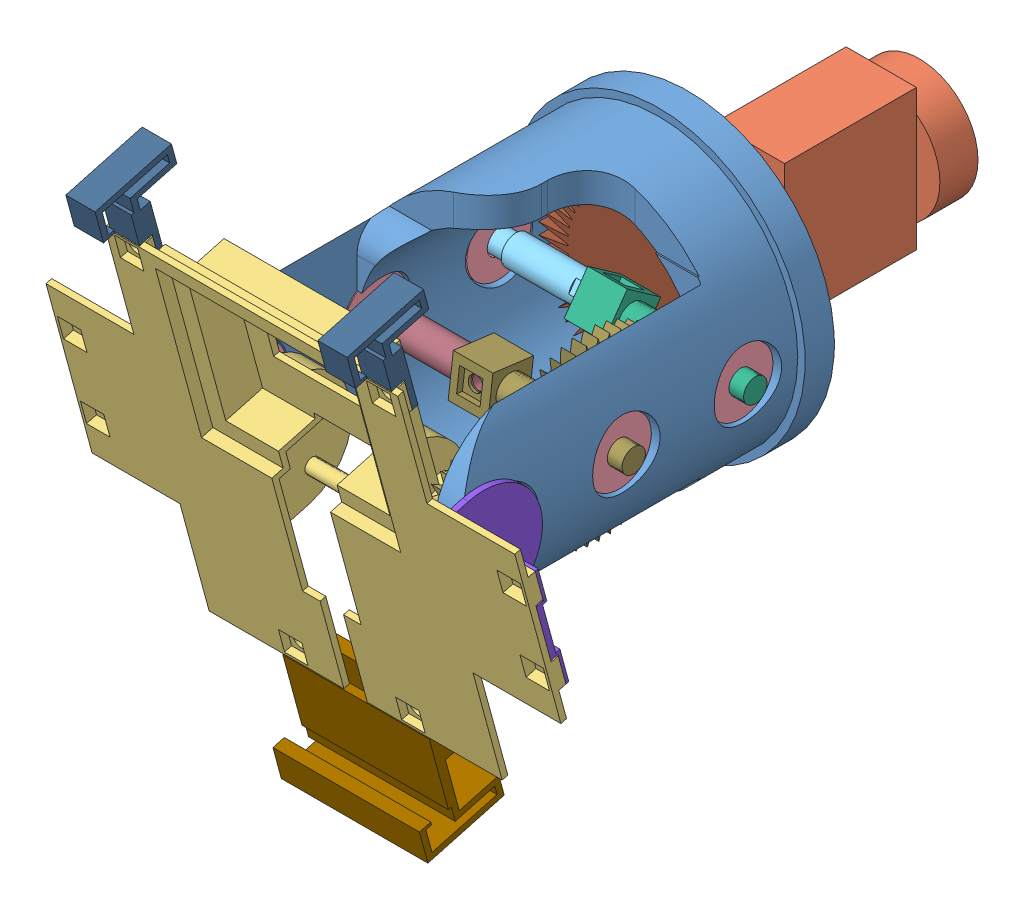
SolidWorks assembly Assemblagefinal, configuration Défaut. Lengths in mm.
Overall size (160 193.33 243.82).
20 component instances, 13 part files, 45 mates.
Components (placement in the parent):
- test taille plateforme3-1: test taille plateforme3 [Défaut] at (-13.313 4.6457 79) size (100 100 136)
- piece dessous-1: piece dessous [Défaut] at (-13.313 4.6457 58) size (40 48 68)
- Fixation Panneau2-1: Fixation Panneau2 [Défaut] at (-12.813 -1.2497 210.7139) x (-1 0 0) z (0 0.262019 -0.965063) size (160 136 37.5)
- Roulement-1: Roulement [Défaut] at (24.687 4.6457 106) x (0 0 -1) z (1 0 0) size (22 22 7)
- Roulement-2: Roulement [Défaut] at (24.687 4.6457 147.5) x (0 0 -1) z (1 0 0) size (22 22 7)
- Roulement-3: Roulement [Défaut] at (24.687 4.6457 189) x (0 0 -1) z (1 0 0) size (22 22 7)
- Roulement-4: Roulement [Défaut] at (-58.313 4.6457 189) x (0 0 -1) z (1 0 0) size (22 22 7)
- Roulement-5: Roulement [Défaut] at (-58.313 4.6457 147.5) x (0 0 -1) z (1 0 0) size (22 22 7)
- Roulement-6: Roulement [Défaut] at (-57.813 4.6457 106) x (0 0 -1) z (1 0 0) size (22 22 7)
- Roulement-7: Roulement [Défaut] at (-13.313 4.6457 1) x (0.817339 -0.576157 0) z (0 0 1) size (22 22 7)
- First engrenage2-1: First engrenage2 [Défaut] at (-45.313 5.0542 105.7118) x (0 -0.817119 0.576469) z (1 0 0) size (10 10 50)
- First engrenage1-1: First engrenage1 [Défaut] at (-45.313 4.6457 106) x (0 -0.817119 0.576469) z (1 0 0) size (30 30 55.5)
- Fixation de la fixation-1: Fixation de la fixation [Défaut] at (-60.813 18.5755 214.0242) x (1 0 0) z (0 0.262019 -0.965063) size (60 40 30)
- Fixation de la fixation2-1: Fixation de la fixation2 [Défaut] at (35.187 -20.027 203.5434) x (-1 0 0) z (0 0.262019 -0.965063) size (46 40 30)
- test accrochev1-1: test accrochev1 [Défaut] at (-37.813 -81.3084 186.9052) x (-1 0 0) z (0 -0.262019 0.965063) size (50 45.5 27)
- test accrochev2-1: test accrochev2 [Défaut] at (35.187 66.3461 226.9941) x (1 0 0) z (0 -0.262019 0.965063) size (10 31.5 27)
- test accrochev2-2: test accrochev2 [Défaut] at (-50.813 66.3461 226.9941) x (1 0 0) z (0 -0.262019 0.965063) size (10 31.5 27)
- Pièce3-1: Pièce3 [Défaut] at (-13.313 4.6457 95) x (-0.925124 0.379665 0) z (0 0 -1) size (70 70 36)
- Second engrenage2-1: Second engrenage2 [Défaut] at (-45.313 4.6457 147.5) x (0 -0.126763 -0.991933) z (1 0 0) size (60 60 55.5)
- Second engrenage1-1: Second engrenage1 [Défaut] at (-45.313 4.6457 147.5) x (0 -0.991933 0.126763) z (1 0 0) size (10 10 50)
Mates (geometry in assembly coordinates):
- Coaxiale6: concentric anti-aligned: cylinder of test taille plateforme3-1 through (-13.313 4.6457 184) axis (0 0 -1) radius 5.5; cylinder of piece dessous-1 through (-13.313 4.6457 58) axis (0 0 1) radius 5.5
- Parallèle4: parallel aligned: plane of test taille plateforme3-1 through (-51.313 4.6457 79) normal (1 0 0); plane of piece dessous-1 through (-4.2763 4.6457 58) normal (1 0 0)
- Coïncidente2: coincident anti-aligned: plane of test taille plateforme3-1 through (-13.313 4.6457 68) normal (0 0 -1); plane of piece dessous-1 through (-13.313 4.6457 68) normal (0 0 1)
- Coaxiale8: concentric anti-aligned: cylinder of test taille plateforme3-1 through (-63.313 4.6457 189) axis (1 0 0) radius 11.5; cylinder of Roulement-3 through (31.687 4.6457 189) axis (-1 0 0) radius 11
- Coïncidente3: coincident aligned: plane of test taille plateforme3-1 through (24.687 4.6457 239) normal (-1 0 0); plane of Roulement-3 through (24.687 4.6457 189) normal (-1 0 0)
- Coaxiale9: concentric anti-aligned: cylinder of test taille plateforme3-1 through (-63.313 4.6457 147.5) axis (1 0 0) radius 11.5; cylinder of Roulement-2 through (31.687 4.6457 147.5) axis (-1 0 0) radius 11
- Coïncidente4: coincident aligned: plane of test taille plateforme3-1 through (24.687 4.6457 239) normal (-1 0 0); plane of Roulement-2 through (24.687 4.6457 147.5) normal (-1 0 0)
- Coaxiale10: concentric anti-aligned: cylinder of test taille plateforme3-1 through (-63.313 4.6457 106) axis (1 0 0) radius 11.5; cylinder of Roulement-1 through (31.687 4.6457 106) axis (-1 0 0) radius 11
- Coïncidente5: coincident aligned: plane of test taille plateforme3-1 through (24.687 4.6457 239) normal (-1 0 0); plane of Roulement-1 through (24.687 4.6457 106) normal (-1 0 0)
- Coaxiale11: concentric anti-aligned: cylinder of Fixation Panneau2-1 through (21.187 4.6457 189) axis (1 0 0) radius 4.5; cylinder of Roulement-3 through (31.687 4.6457 189) axis (-1 0 0) radius 4
- Coaxiale13: concentric aligned: cylinder of piece dessous-1 through (-13.313 4.6457 8) axis (0 0 -1) radius 11.5; cylinder of Roulement-7 through (-13.313 4.6457 8) axis (0 0 -1) radius 11
- Coïncidente6: coincident anti-aligned: plane of piece dessous-1 through (-13.313 4.6457 8) normal (0 0 -1); plane of Roulement-7 through (-13.313 4.6457 8) normal (0 0 1)
- Coaxiale14: concentric anti-aligned: cylinder of test taille plateforme3-1 through (-63.313 4.6457 189) axis (1 0 0) radius 11.5; cylinder of Roulement-4 through (-51.313 4.6457 189) axis (-1 0 0) radius 11
- Coaxiale15: concentric anti-aligned: cylinder of test taille plateforme3-1 through (-63.313 4.6457 147.5) axis (1 0 0) radius 11.5; cylinder of Roulement-5 through (-51.313 4.6457 147.5) axis (-1 0 0) radius 11
- Coaxiale16: concentric anti-aligned: cylinder of test taille plateforme3-1 through (-63.313 4.6457 106) axis (1 0 0) radius 11.5; cylinder of Roulement-6 through (-50.813 4.6457 106) axis (-1 0 0) radius 11
- Coïncidente7: coincident aligned: plane of test taille plateforme3-1 through (-51.313 4.6457 79) normal (1 0 0); plane of Roulement-4 through (-51.313 4.6457 189) normal (1 0 0)
- Coïncidente8: coincident aligned: plane of test taille plateforme3-1 through (-51.313 4.6457 79) normal (1 0 0); plane of Roulement-5 through (-51.313 4.6457 147.5) normal (1 0 0)
- Tangent1: tangent anti-aligned: cylinder of test taille plateforme3-1 through (-13.313 4.6457 204) axis (0 0 -1) radius 37.5; plane of Roulement-6 through (-50.813 4.6457 106) normal (1 0 0)
- Coaxiale17: concentric aligned: cylinder of Roulement-4 through (-51.313 4.6457 189) axis (-1 0 0) radius 4; cylinder of Fixation de la fixation-1 through (-32.813 4.6457 189) axis (-1 0 0) radius 4
- Coïncidente10: coincident anti-aligned: plane of Fixation Panneau2-1 through (-12.813 -0.7257 208.7838) normal (0 0.262019 -0.965063); plane of Fixation de la fixation-1 through (-60.813 18.5755 214.0242) normal (0 -0.262019 0.965063)
- Coaxiale18: concentric aligned: cylinder of Fixation Panneau2-1 through (-87.813 -16.6428 210.1613) axis (0 0.262019 -0.965063) radius 2.5; cylinder of Fixation de la fixation-1 through (-87.813 -17.0358 211.6089) axis (0 0.262019 -0.965063) radius 2.5
- Coaxiale19: concentric aligned: cylinder of Fixation Panneau2-1 through (21.187 4.6457 189) axis (1 0 0) radius 4.5; cylinder of Fixation de la fixation2-1 through (21.187 4.6457 189) axis (1 0 0) radius 4
- Coïncidente11: coincident anti-aligned: plane of Fixation Panneau2-1 through (-12.813 -0.7257 208.7838) normal (0 0.262019 -0.965063); plane of Fixation de la fixation2-1 through (35.187 -20.027 203.5434) normal (0 -0.262019 0.965063)
- Coaxiale20: concentric aligned: cylinder of Fixation Panneau2-1 through (62.187 12.3091 218.0219) axis (0 0.262019 -0.965063) radius 2.5; cylinder of Fixation de la fixation2-1 through (62.187 11.9161 219.4695) axis (0 0.262019 -0.965063) radius 2.5
- Coïncidente12: coincident anti-aligned: plane of test taille plateforme3-1 through (24.687 4.6457 239) normal (-1 0 0); plane of Fixation Panneau2-1 through (24.687 4.6457 189) normal (1 0 0)
- Coaxiale21: concentric aligned: cylinder of Fixation Panneau2-1 through (30.187 60.2042 224.8085) axis (0 0.262019 -0.965063) radius 2.5; cylinder of test accrochev2-1 through (30.187 50.7716 259.5507) axis (0 0.262019 -0.965063) radius 2.5
- Coïncidente13: coincident anti-aligned: plane of Fixation Panneau2-1 through (-12.813 -0.0707 206.3711) normal (0 0.262019 -0.965063); plane of test accrochev2-1 through (35.187 55.903 221.5682) normal (0 -0.262019 0.965063)
- Parallèle5: parallel anti-aligned: plane of Fixation Panneau2-1 through (-12.813 64.8986 226.6011) normal (0 0.965063 0.262019); plane of test accrochev2-1 through (35.187 65.3811 226.7321) normal (0 -0.965063 -0.262019)
- Coaxiale22: concentric aligned: cylinder of Fixation Panneau2-1 through (-32.813 -61.3937 191.794) axis (0 0.262019 -0.965063) radius 2.5; cylinder of test accrochev1-1 through (-32.813 -62.9658 197.5844) axis (0 0.262019 -0.965063) radius 2.5
- Parallèle6: parallel anti-aligned: plane of Fixation Panneau2-1 through (-12.813 -66.35 190.9665) normal (0 -0.965063 -0.262019); plane of test accrochev1-1 through (-37.813 -66.8325 190.8355) normal (0 0.965063 0.262019)
- Coïncidente17: coincident anti-aligned: plane of Fixation Panneau2-1 through (-12.813 -0.0707 206.3711) normal (0 0.262019 -0.965063); plane of test accrochev1-1 through (12.187 -56.0443 191.174) normal (0 -0.262019 0.965063)
- Coaxiale23: concentric aligned: cylinder of Fixation Panneau2-1 through (-55.813 60.2042 224.8085) axis (0 0.262019 -0.965063) radius 2.5; cylinder of test accrochev2-2 through (-55.813 50.7716 259.5507) axis (0 0.262019 -0.965063) radius 2.5
- Coïncidente18: coincident anti-aligned: plane of Fixation Panneau2-1 through (-12.813 -0.0707 206.3711) normal (0 0.262019 -0.965063); plane of test accrochev2-2 through (-50.813 55.903 221.5682) normal (0 -0.262019 0.965063)
- Parallèle7: parallel anti-aligned: plane of Fixation Panneau2-1 through (-12.813 64.8986 226.6011) normal (0 0.965063 0.262019); plane of test accrochev2-2 through (-50.813 65.3811 226.7321) normal (0 -0.965063 -0.262019)
- Coaxiale24: concentric aligned: cylinder of First engrenage2-1 through (-12.313 11.9998 100.8118) axis (0 -0.817119 0.576469) radius 2.5; cylinder of First engrenage1-1 through (-12.313 2.1943 107.7294) axis (0 -0.817119 0.576469) radius 2.5
- Parallèle8: parallel anti-aligned: plane of First engrenage2-1 through (-19.313 5.8965 100.8342) normal (0 -0.576469 -0.817119); plane of First engrenage1-1 through (-14.813 -0.9287 105.0374) normal (0 0.576469 0.817119)
- Coïncidente21: coincident anti-aligned: plane of First engrenage2-1 through (-19.313 5.8965 100.8342) normal (0 0.817119 -0.576469); plane of First engrenage1-1 through (-14.813 10.22 106.9626) normal (0 -0.817119 0.576469)
- Coïncidente22: coincident anti-aligned: plane of test taille plateforme3-1 through (24.687 4.6457 239) normal (-1 0 0); plane of First engrenage1-1 through (24.687 4.6457 106) normal (1 0 0)
- Coaxiale26: concentric anti-aligned: cylinder of test taille plateforme3-1 through (-13.313 4.6457 184) axis (0 0 -1) radius 5.5; cylinder of Pièce3-1 through (-13.313 4.6457 59) axis (0 0 1) radius 5
- Coïncidente23: coincident anti-aligned: plane of test taille plateforme3-1 through (-13.313 4.6457 89) normal (0 0 1); plane of Pièce3-1 through (-13.313 4.6457 89) normal (0 0 -1)
- Coaxiale27: concentric anti-aligned: cylinder of Roulement-1 through (31.687 4.6457 106) axis (-1 0 0) radius 4; cylinder of First engrenage1-1 through (24.687 4.6457 106) axis (1 0 0) radius 4
- Coaxiale30: concentric anti-aligned: cylinder of Roulement-2 through (31.687 4.6457 147.5) axis (-1 0 0) radius 4; cylinder of Second engrenage2-1 through (24.687 4.6457 147.5) axis (1 0 0) radius 4
- Coïncidente25: coincident anti-aligned: plane of test taille plateforme3-1 through (24.687 4.6457 239) normal (-1 0 0); plane of Second engrenage2-1 through (24.687 4.6457 147.5) normal (1 0 0)
- Coaxiale31: concentric aligned: cylinder of Roulement-5 through (-51.313 4.6457 147.5) axis (-1 0 0) radius 4; cylinder of Second engrenage1-1 through (-45.313 4.6457 147.5) axis (-1 0 0) radius 4
- Coaxiale32: concentric anti-aligned: cylinder of Second engrenage2-1 through (-12.313 5.026 150.4758) axis (0 0.126763 0.991933) radius 2.5; cylinder of Second engrenage1-1 through (-12.313 5.2795 152.4597) axis (0 -0.126763 -0.991933) radius 2.5
